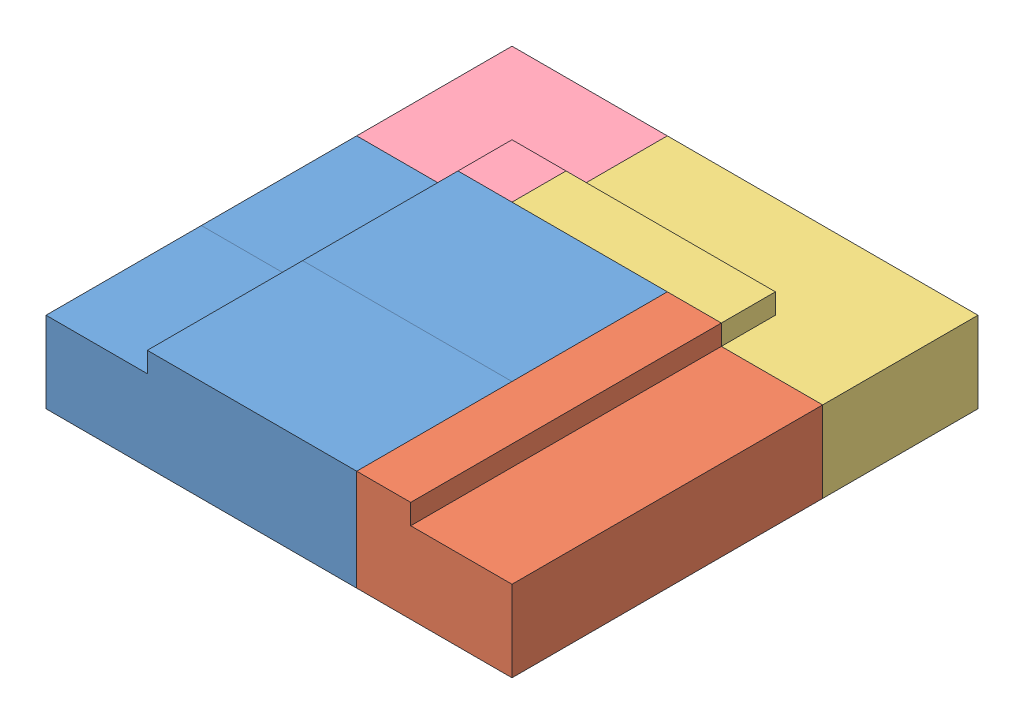
SolidWorks assembly Assem5, configuration Default. Lengths in mm.
Overall size (345 75 345).
5 component instances, 4 part files, 8 mates.
Components (placement in the parent):
- Brick-Sharp-BackCut-1: Brick-Sharp-BackCut [Default] at (102.0414 124.8114 164.7515) size (230 75 115)
- Brick-Sharp-SideCut-1: Brick-Sharp-SideCut [Default] at (274.5414 124.8114 107.2515) x (0 0 1) z (-1 0 0) size (230 75 115)
- Brick-Sharp-BackCut-2: Brick-Sharp-BackCut [Default] at (102.0414 124.8114 49.7515) size (230 75 115)
- Brick-Sharp-BackLeftCut-1: Brick-Sharp-BackLeftCut [Default] at (217.0414 124.8114 -65.2485) x (-1 0 0) z (0 0 -1) size (230 75 115)
- Brick-Sharp-BackRightCutTrimmed-1: Brick-Sharp-BackRightCutTrimmed [Default] at (102.0414 124.8114 -65.2485) size (115 75 115)
Mates (geometry in assembly coordinates):
- Coincident1: coincident anti-aligned: plane of Brick-Sharp-BackCut-1 through (217.0414 162.3114 107.2515) normal (1 0 0); plane of Brick-Sharp-SideCut-1 through (217.0414 162.3114 -7.7485) normal (-1 0 0)
- Coincident2: coincident aligned: line of Brick-Sharp-BackCut-1 through (217.0414 162.3114 222.2515) axis (0 -1 0); line of Brick-Sharp-SideCut-1 through (217.0414 162.3114 222.2515) axis (0 -1 0)
- Coincident3: coincident anti-aligned: line of Brick-Sharp-BackCut-1 through (217.0414 162.3114 222.2515) axis (0 0 -1); line of Brick-Sharp-SideCut-1 through (217.0414 162.3114 -7.7485) axis (0 0 1)
- Coincident5: coincident: plane of Brick-Sharp-BackCut-2 through (-12.9586 162.3114 -7.7485) normal (0 0 -1); plane of Brick-Sharp-BackLeftCut-1 through (332.0414 162.3114 -7.7485) normal (0 0 1)
- Coincident6: coincident: line of Brick-Sharp-SideCut-1 through (332.0414 147.3114 222.2515) axis (0 0 -1); line of Brick-Sharp-BackLeftCut-1 through (332.0414 147.3114 -7.7485) axis (0 0 -1)
- Coincident7: coincident anti-aligned: line of Brick-Sharp-BackCut-2 through (217.0414 162.3114 -7.7485) axis (-1 0 0); line of Brick-Sharp-BackLeftCut-1 through (102.0414 162.3114 -7.7485) axis (1 0 0)
- Coincident8: coincident: line of Brick-Sharp-BackCut-2 through (-12.9586 147.3114 -7.7485) axis (0 -1 0); line of Brick-Sharp-BackRightCutTrimmed-1 through (-12.9586 147.3114 -7.7485) axis (0 -1 0)
- Coincident9: coincident aligned: line of Brick-Sharp-BackLeftCut-1 through (332.0414 87.3114 -122.7485) axis (-1 0 0); line of Brick-Sharp-BackRightCutTrimmed-1 through (102.0414 87.3114 -122.7485) axis (-1 0 0)
